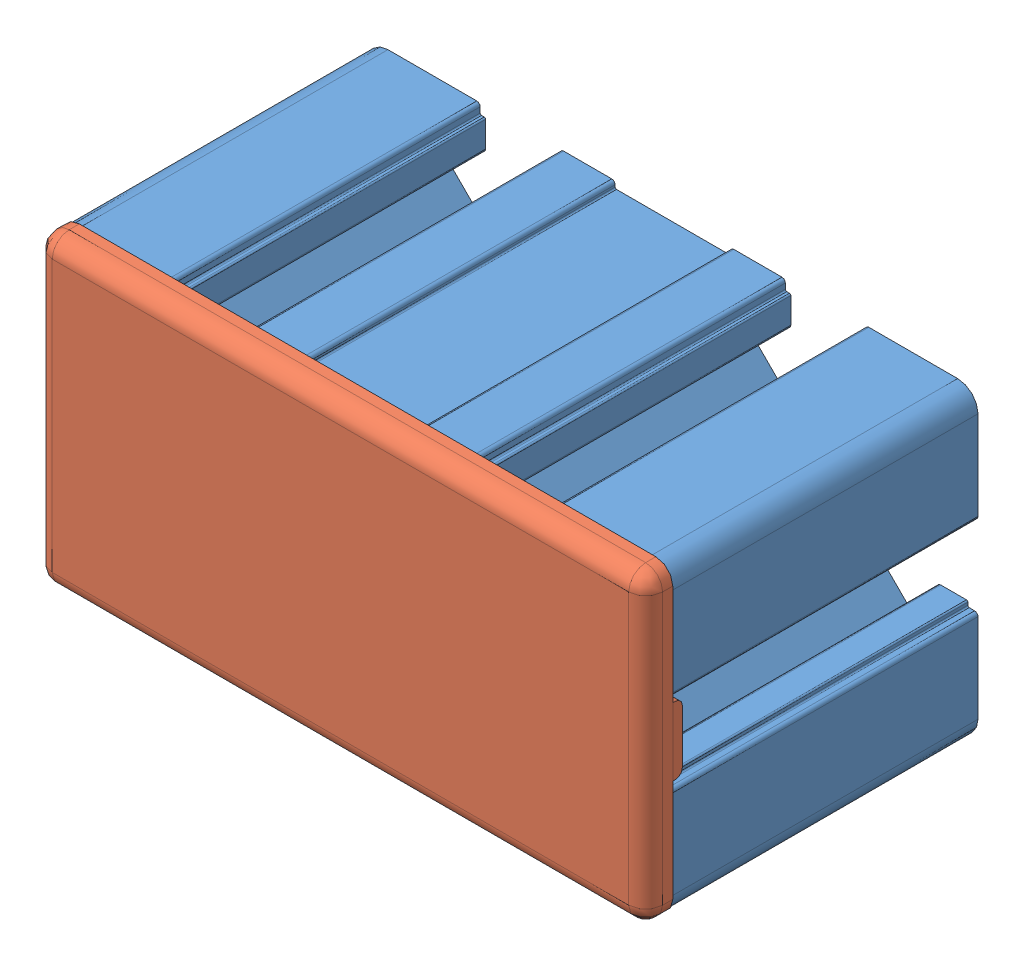
SolidWorks assembly Заглушка45х90СБ, configuration По умолчанию. Lengths in mm.
Overall size (90 45 49).
2 component instances, 2 part files, 6 mates.
Components (placement in the parent):
- 45х90 заглушка-1: 45х90 заглушка [По умолчанию] at origin size (90 45 45)
- Заглушка торцевая 45х90-1: Заглушка торцевая 45х90 [По умолчанию] at (-4.9414 35.2231 47) x (0 0 -1) z (0 1 0) size (13 90 45)
Mates (geometry in assembly coordinates):
- Совпадение2: coincident: point of 45х90 заглушка-1
- Параллельность1: parallel anti-aligned: plane of 45х90 заглушка-1 through (0 13.7231 45) normal (0 -1 0)
- Совпадение4: coincident anti-aligned: plane of 45х90 заглушка-1 through (0 0 0) normal (0 0 -1)
- Совпадение5: coincident anti-aligned: plane of 45х90 заглушка-1 through (0 0 45) normal (0 0 1); plane of Заглушка торцевая 45х90-1 through (40.0586 12.7231 45) normal (0 0 -1)
- Совпадение6: coincident aligned: plane of 45х90 заглушка-1 through (0 57.7231 45) normal (0 1 0); plane of Заглушка торцевая 45х90-1 through (-47.4414 57.7231 46.5) normal (0 1 0)
- Совпадение7: coincident aligned: plane of 45х90 заглушка-1 through (40.0586 0 45) normal (1 0 0); plane of Заглушка торцевая 45х90-1 through (40.0586 12.7231 46.5) normal (1 0 0)
